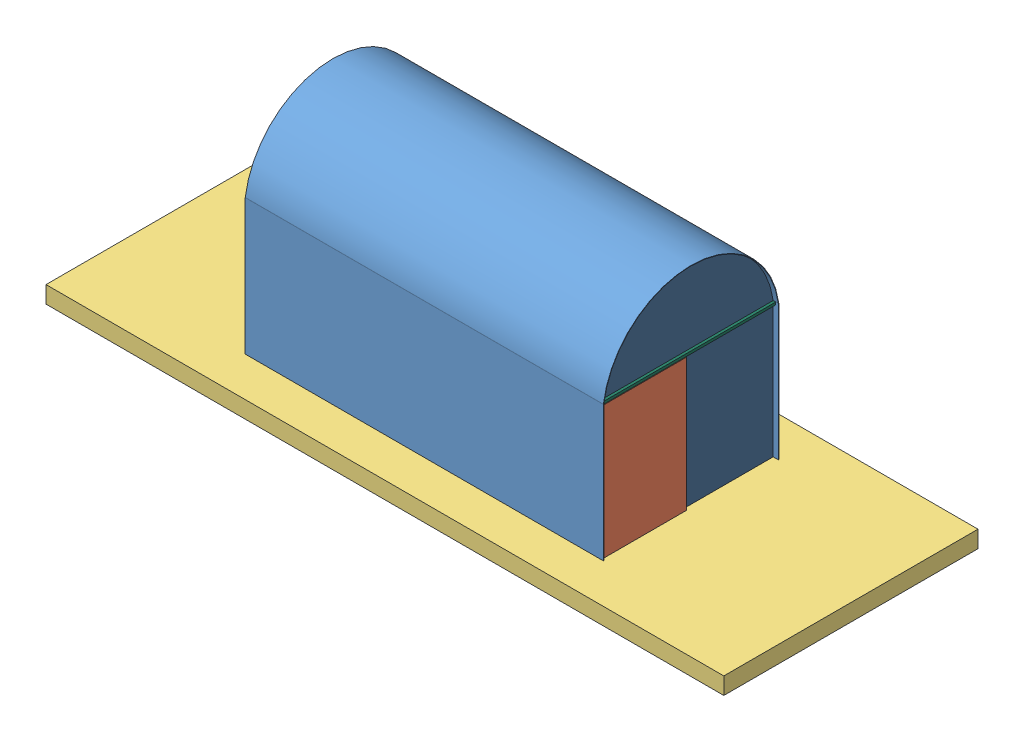
SolidWorks assembly SolarDryer, configuration Default. Lengths in mm.
Overall size (8000 2703.29 3000).
127 component instances, 22 part files, 14 mates.
Components (placement in the parent):
- Dome_-1: Dome_ [Default] x (-1 0 0) z (0 0 -1) size (4227 2503.29 2069.91)
- SolarDryer_Frame-1: SolarDryer_Frame [Default] at (-4192.3996 -838.53 0) x (0 0 1) z (-1 0 0) size (2062 2546.04 4095)
  - Vertical joint-1: Vertical joint [Default] at (-1015 770.5 -2160.8996) size (32 80 32)
  - VerticalBar-1: VerticalBar [Default] at (-425 0 -2160.8996) x (-1 0 0) z (0 0 1) size (30 1615 30)
  - Wrapper-1: Wrapper [Default] at (-425 780.5 -2160.8996) x (0 0 -1) z (0 1 0) size (22 32 30)
  - Arc_Bar-1: Arc_Bar [Default] at (0 838.5301 -2160.8996) x (0 0 -1) z (1 0 0) size (30.03 960.01 2060)
  - LateralBar-1: LateralBar [Default] at (0 826.5 -2160.8996) x (0 0 -1) z (1 0 0) size (30 30 1992)
  - Back_Wall-1: Back_Wall [Default] at (0 800 -2178.3996) size (2060 2500 5) (hidden)
  - Wrapper-4: Wrapper [Default] at (-1027 826.5 -2160.8996) x (0 1 0) z (1 0 0) size (22 32 30)
  - Wrapper-5: Wrapper [Default] at (-969 826.5 -2160.8996) x (0 0 1) z (-1 0 0) size (22 32 30)
  - VerticalBar_Corners-1: VerticalBar_Corners [Default] at (-1015 -14.4849 -2160.8996) size (30 1586.03 30)
  - Wrapper-8: Wrapper [Default] at (-425 838.5 -2160.8996) x (1 0 0) z (0 -1 0) size (22 32 30)
  - VerticalBar-2: VerticalBar [Default] at (425 0 -2160.8996) x (1 0 0) z (0 0 -1) size (30 1615 30)
  - Wrapper-9: Wrapper [Default] at (425 838.5 -2160.8996) x (1 0 0) z (0 -1 0) size (22 32 30)
  - Wrapper-10: Wrapper [Default] at (425 780.5 -2160.8996) x (0 0 1) z (0 1 0) size (22 32 30)
  - VerticalBar_Corners-2: VerticalBar_Corners [Default] at (1015 -14.4849 -2160.8996) x (-1 0 0) z (0 0 -1) size (30 1586.03 30)
  - Vertical joint-2: Vertical joint [Default] at (1015 770.5 -2160.8996) x (-1 0 0) z (0 0 -1) size (32 80 32)
  - Wrapper-11: Wrapper [Default] at (1027 826.5 -2160.8996) x (0 -1 0) z (-1 0 0) size (22 32 30)
  - Wrapper-12: Wrapper [Default] at (969 826.5 -2160.8996) x (0 0 -1) z (1 0 0) size (22 32 30)
  - VerticalBar_Corners-7: VerticalBar_Corners [Default] at (-1015 -14.4849 -4192.3996) size (30 1586.03 30)
  - VerticalBar_Corners-8: VerticalBar_Corners [Default] at (-1015 -14.4849 -6223.8996) size (30 1586.03 30)
  - Vertical joint-7: Vertical joint [Default] at (-1015 770.5 -4192.3996) size (32 80 32)
  - Vertical joint-8: Vertical joint [Default] at (-1015 770.5 -6223.8996) size (32 80 32)
  - VerticalBar_Corners-9: VerticalBar_Corners [Default] at (1015 -14.4849 -4192.3996) x (-1 0 0) z (0 0 -1) size (30 1586.03 30)
  - VerticalBar_Corners-10: VerticalBar_Corners [Default] at (1015 -14.4849 -6223.8996) x (-1 0 0) z (0 0 -1) size (30 1586.03 30)
  - Vertical joint-9: Vertical joint [Default] at (1015 770.5 -4192.3996) x (-1 0 0) z (0 0 -1) size (32 80 32)
  - Vertical joint-10: Vertical joint [Default] at (1015 770.5 -6223.8996) x (-1 0 0) z (0 0 -1) size (32 80 32)
  - Arc_Bar-4: Arc_Bar [Default] at (0 838.5301 -4192.3996) x (0 0 -1) z (1 0 0) size (30.03 960.01 2060)
  - Arc_Bar-5: Arc_Bar [Default] at (0 838.5301 -6223.8996) x (0 0 -1) z (1 0 0) size (30.03 960.01 2060)
  - Wrapper-13: Wrapper [Default] at (1015 719.5 -2148.8996) x (0 1 0) z (0 0 -1) size (22 32 30)
  - Wrapper-15: Wrapper [Default] at (1015 717.5 -2206.8996) size (22 32 30)
  - Wrapper-16: Wrapper [Default] at (1015 719.5 -4204.3996) x (0 -1 0) z (0 0 1) size (22 32 30)
  - Wrapper-17: Wrapper [Default] at (1015 717.5 -4146.3996) x (-1 0 0) z (0 0 -1) size (22 32 30)
  - HorizontalBarSides-1: HorizontalBarSides [Default] at (1015 717.5 -4174.3996) size (30 30 1995.5)
  - Wrapper-22: Wrapper [Default] at (1015 697.5 -4180.3996) x (0 1 0) z (0 0 -1) size (22 32 30)
  - Wrapper-23: Wrapper [Default] at (1015 695.5 -4238.3996) size (22 32 30)
  - HorizontalBarSides-3: HorizontalBarSides [Default] at (1015 695.5 -6205.8996) size (30 30 1995.5)
  - Wrapper-24: Wrapper [Default] at (1015 697.5 -6235.8996) x (0 -1 0) z (0 0 1) size (22 32 30)
  - Wrapper-25: Wrapper [Default] at (1015 695.5 -6177.8996) x (-1 0 0) z (0 0 -1) size (22 32 30)
  - Wrapper-26: Wrapper [Default] at (1015 147.5 -6235.8996) x (0 -1 0) z (0 0 1) size (22 32 30)
  - Wrapper-27: Wrapper [Default] at (1015 -402.5 -6235.8996) x (0 -1 0) z (0 0 1) size (22 32 30)
  - Wrapper-28: Wrapper [Default] at (1015 145.5 -6177.8996) x (-1 0 0) z (0 0 -1) size (22 32 30)
  - Wrapper-29: Wrapper [Default] at (1015 -404.5 -6177.8996) x (-1 0 0) z (0 0 -1) size (22 32 30)
  - HorizontalBarSides-4: HorizontalBarSides [Default] at (1015 145.5 -6205.8996) size (30 30 1995.5)
  - HorizontalBarSides-5: HorizontalBarSides [Default] at (1015 -404.5 -6205.8996) size (30 30 1995.5)
  - Wrapper-30: Wrapper [Default] at (1015 145.5 -4238.3996) size (22 32 30)
  - Wrapper-31: Wrapper [Default] at (1015 -404.5 -4238.3996) size (22 32 30)
  - Wrapper-32: Wrapper [Default] at (1015 147.5 -4180.3996) x (0 1 0) z (0 0 -1) size (22 32 30)
  - Wrapper-33: Wrapper [Default] at (1015 -402.5 -4180.3996) x (0 1 0) z (0 0 -1) size (22 32 30)
  - Wrapper-34: Wrapper [Default] at (1015 169.5 -4204.3996) x (0 -1 0) z (0 0 1) size (22 32 30)
  - Wrapper-35: Wrapper [Default] at (1015 -380.5 -4204.3996) x (0 -1 0) z (0 0 1) size (22 32 30)
  - Wrapper-36: Wrapper [Default] at (1015 167.5 -4146.3996) x (-1 0 0) z (0 0 -1) size (22 32 30)
  - Wrapper-37: Wrapper [Default] at (1015 -382.5 -4146.3996) x (-1 0 0) z (0 0 -1) size (22 32 30)
  - HorizontalBarSides-6: HorizontalBarSides [Default] at (1015 167.5 -4174.3996) size (30 30 1995.5)
  - HorizontalBarSides-7: HorizontalBarSides [Default] at (1015 -382.5 -4174.3996) size (30 30 1995.5)
  - Wrapper-38: Wrapper [Default] at (1015 169.5 -2148.8996) x (0 1 0) z (0 0 -1) size (22 32 30)
  - Wrapper-39: Wrapper [Default] at (1015 -380.5 -2148.8996) x (0 1 0) z (0 0 -1) size (22 32 30)
  - Wrapper-40: Wrapper [Default] at (1015 167.5 -2206.8996) size (22 32 30)
  - Wrapper-41: Wrapper [Default] at (1015 -382.5 -2206.8996) size (22 32 30)
  - Wrapper-42: Wrapper [Default] at (-1015 697.5 -6235.8996) x (0 1 0) z (0 0 1) size (22 32 30)
  - Wrapper-43: Wrapper [Default] at (-1015 695.5 -6177.8996) x (-1 0 0) z (0 0 -1) size (22 32 30)
  - HorizontalBarSides-8: HorizontalBarSides [Default] at (-1015 695.5 -4210.3996) x (-1 0 0) z (0 0 -1) size (30 30 1995.5)
  - Wrapper-44: Wrapper [Default] at (-1015 695.5 -4238.3996) size (22 32 30)
  - Wrapper-45: Wrapper [Default] at (-1015 697.5 -4180.3996) x (0 -1 0) z (0 0 -1) size (22 32 30)
  - Wrapper-46: Wrapper [Default] at (-1015 719.5 -4204.3996) x (0 1 0) z (0 0 1) size (22 32 30)
  - Wrapper-47: Wrapper [Default] at (-1015 717.5 -4146.3996) x (-1 0 0) z (0 0 -1) size (22 32 30)
  - HorizontalBarSides-9: HorizontalBarSides [Default] at (-1015 717.5 -2178.8996) x (-1 0 0) z (0 0 -1) size (30 30 1995.5)
  - Wrapper-48: Wrapper [Default] at (-1015 719.5 -2148.8996) x (0 -1 0) z (0 0 -1) size (22 32 30)
  - Wrapper-49: Wrapper [Default] at (-1015 717.5 -2206.8996) size (22 32 30)
  - Wrapper-50: Wrapper [Default] at (-1015 147.5 -6235.8996) x (0 1 0) z (0 0 1) size (22 32 30)
  - Wrapper-51: Wrapper [Default] at (-1015 -402.5 -6235.8996) x (0 1 0) z (0 0 1) size (22 32 30)
  - Wrapper-52: Wrapper [Default] at (-1015 145.5 -6177.8996) x (-1 0 0) z (0 0 -1) size (22 32 30)
  - Wrapper-53: Wrapper [Default] at (-1015 -404.5 -6177.8996) x (-1 0 0) z (0 0 -1) size (22 32 30)
  - HorizontalBarSides-10: HorizontalBarSides [Default] at (-1015 145.5 -4210.3996) x (-1 0 0) z (0 0 -1) size (30 30 1995.5)
  - HorizontalBarSides-11: HorizontalBarSides [Default] at (-1015 -404.5 -4210.3996) x (-1 0 0) z (0 0 -1) size (30 30 1995.5)
  - Wrapper-54: Wrapper [Default] at (-1015 145.5 -4238.3996) size (22 32 30)
  - Wrapper-55: Wrapper [Default] at (-1015 -404.5 -4238.3996) size (22 32 30)
  - Wrapper-56: Wrapper [Default] at (-1015 147.5 -4180.3996) x (0 -1 0) z (0 0 -1) size (22 32 30)
  - Wrapper-57: Wrapper [Default] at (-1015 -402.5 -4180.3996) x (0 -1 0) z (0 0 -1) size (22 32 30)
  - Wrapper-58: Wrapper [Default] at (-1015 169.5 -4204.3996) x (0 1 0) z (0 0 1) size (22 32 30)
  - Wrapper-59: Wrapper [Default] at (-1015 -380.5 -4204.3996) x (0 1 0) z (0 0 1) size (22 32 30)
  - Wrapper-60: Wrapper [Default] at (-1015 167.5 -4146.3996) x (-1 0 0) z (0 0 -1) size (22 32 30)
  - Wrapper-61: Wrapper [Default] at (-1015 -382.5 -4146.3996) x (-1 0 0) z (0 0 -1) size (22 32 30)
  - HorizontalBarSides-12: HorizontalBarSides [Default] at (-1015 167.5 -2178.8996) x (-1 0 0) z (0 0 -1) size (30 30 1995.5)
  - HorizontalBarSides-13: HorizontalBarSides [Default] at (-1015 -382.5 -2178.8996) x (-1 0 0) z (0 0 -1) size (30 30 1995.5)
  - Wrapper-62: Wrapper [Default] at (-1015 169.5 -2148.8996) x (0 -1 0) z (0 0 -1) size (22 32 30)
  - Wrapper-63: Wrapper [Default] at (-1015 -380.5 -2148.8996) x (0 -1 0) z (0 0 -1) size (22 32 30)
  - Wrapper-64: Wrapper [Default] at (-1015 167.5 -2206.8996) size (22 32 30)
  - Wrapper-65: Wrapper [Default] at (-1015 -382.5 -2206.8996) size (22 32 30)
- Back_SolarDryer-1: Back_SolarDryer [Default] at (-2050 -800.159 0) x (0 0 -1) z (1 0 0) size (2060 2500 5)
- FullFront-1: FullFront [Default] at (2050 -800.1591 0) x (0 0 -1) z (1 0 0) size (2060 2500 40)
  - Front_SolarDryer-1: Front_SolarDryer [Default] at origin size (2060 2500 5)
  - FullDoorWithBar-1: FullDoorWithBar [Default] at (0 785 17.5) x (0 0 1) z (-1 0 0) size (30 1600 2060)
    - FullCar-1: FullCar [Default] at (0 -6.25 870) size (25 18.99 35)
      - Carriage-1: Carriage [Default] at origin size (24.16 8.5 35)
      - LockWheels-1: LockWheels [Default] at (12.5 0 7.5) x (0 0.86398 0.503526) z (0 -0.503526 0.86398) size (3.5 7.63 3.5)
      - LockWheels-2: LockWheels [Default] at (12.5 0 -7.5) x (0 -0.86398 0.503526) z (0 -0.503526 -0.86398) size (3.5 7.63 3.5)
      - LockWheels-3: LockWheels [Default] at (-12.5 0 7.5) x (0 -0.86398 -0.503526) z (0 -0.503526 0.86398) size (3.5 7.63 3.5)
      - LockWheels-4: LockWheels [Default] at (-12.5 0 -7.5) x (0 0.86398 -0.503526) z (0 -0.503526 -0.86398) size (3.5 7.63 3.5)
      - WheelCarriage-1: WheelCarriage [Default] at (9.25 0 7.5) x (0 -0.862763 -0.505608) z (1 0 0) size (13.5 13.5 3.5)
      - WheelCarriage-2: WheelCarriage [Default] at (9.25 0 -7.5) x (0 -0.862763 0.505608) z (-1 0 0) size (13.5 13.5 3.5)
      - WheelCarriage-3: WheelCarriage [Default] at (-9.25 0 7.5) x (0 -0.862763 -0.505608) z (1 0 0) size (13.5 13.5 3.5)
      - WheelCarriage-4: WheelCarriage [Default] at (-9.25 0 -7.5) x (0 -0.862763 0.505608) z (-1 0 0) size (13.5 13.5 3.5)
      - Support-1: Support [Default] at (0 -7.5 0) x (0 0 1) z (-1 0 0) size (13 7.5 7)
    - FrontHorizontalBar-1: FrontHorizontalBar [Default] at origin size (30 30 2060)
    - Door-1: Door [Default] at (0 -801.125 530) x (0 0 1) z (-1 0 0) size (1000 1572.75 30)
    - Lid_Locker-1: Lid_Locker [Default] at (-3.725 -13.75 870) x (0 0 1) z (-1 0 0) size (13.9 5.5 1.7)
    - FullCar-4: FullCar [Default] at (0 -6.25 190) size (25 18.99 35)
      - Carriage-1: Carriage [Default] at origin size (24.16 8.5 35)
      - LockWheels-1: LockWheels [Default] at (12.5 0 7.5) x (0 0.86398 0.503526) z (0 -0.503526 0.86398) size (3.5 7.63 3.5)
      - LockWheels-2: LockWheels [Default] at (12.5 0 -7.5) x (0 -0.86398 0.503526) z (0 -0.503526 -0.86398) size (3.5 7.63 3.5)
      - LockWheels-3: LockWheels [Default] at (-12.5 0 7.5) x (0 -0.86398 -0.503526) z (0 -0.503526 0.86398) size (3.5 7.63 3.5)
      - LockWheels-4: LockWheels [Default] at (-12.5 0 -7.5) x (0 0.86398 -0.503526) z (0 -0.503526 -0.86398) size (3.5 7.63 3.5)
      - WheelCarriage-1: WheelCarriage [Default] at (9.25 0 7.5) x (0 -0.862763 -0.505608) z (1 0 0) size (13.5 13.5 3.5)
      - WheelCarriage-2: WheelCarriage [Default] at (9.25 0 -7.5) x (0 -0.862763 0.505608) z (-1 0 0) size (13.5 13.5 3.5)
      - WheelCarriage-3: WheelCarriage [Default] at (-9.25 0 7.5) x (0 -0.862763 -0.505608) z (1 0 0) size (13.5 13.5 3.5)
      - WheelCarriage-4: WheelCarriage [Default] at (-9.25 0 -7.5) x (0 -0.862763 0.505608) z (-1 0 0) size (13.5 13.5 3.5)
      - Support-1: Support [Default] at (0 -7.5 0) x (0 0 1) z (-1 0 0) size (13 7.5 7)
    - Lid_Locker-2: Lid_Locker [Default] at (-3.725 -13.75 190) x (0 0 1) z (-1 0 0) size (13.9 5.5 1.7)
    - Full_Restrictor-1: Full_Restrictor [Default] at (0 -12.75 897.6) x (-1 0 0) z (0 0 -1) size (25 10.16 20.1)
      - Lid_Restrictor-1: Lid_Restrictor [Default] at (0 8.5 10.1) x (1 0 0) z (0 0 -1) size (2.81 2.81 3)
      - Restrictor-1: Restrictor [Default] at origin size (25 9.5 19.9)
    - Full_Restrictor-2: Full_Restrictor [Default] at (0 -12.75 -897.6) size (25 10.16 20.1)
      - Lid_Restrictor-1: Lid_Restrictor [Default] at (0 8.5 10.1) x (1 0 0) z (0 0 -1) size (2.81 2.81 3)
      - Restrictor-1: Restrictor [Default] at origin size (25 9.5 19.9)
  - DoorCover-1: DoorCover [Default] at (-530 -16.125 35) size (1000 1567.75 5)
- Floor-1: Floor [Default] at (0 -1698.2927 0) x (-1 0 0) z (0 0 1) size (8000 200 3000)
Mates (geometry in assembly coordinates):
- Coincident6: coincident anti-aligned: plane of Dome_-1; plane of SolarDryer_Frame-1 through (-4192.3996 -838.53 0) normal (0 0 1)
- Coincident7: coincident anti-aligned: plane of Dome_-1 through (0 0 0) normal (-1 0 0)
- Coincident8: coincident anti-aligned: unknown of Dome_-1
- Coincident9: coincident aligned: plane of Dome_-1 through (0 0 0) normal (0 1 0)
- Coincident10: coincident anti-aligned: plane of Dome_-1 through (0 0 0) normal (-1 0 0)
- Tangent1: tangent aligned: cylinder of Dome_-1 through (-2113.5 -139.548 0) axis (1 0 0) radius 1039.548; face of SolarDryer_Frame-1/Arc_Bar-1
- Coincident13: coincident anti-aligned: plane of SolarDryer_Frame-1/Wrapper-9 through (-2047.5 -27.03 414) normal (-1 0 0); plane of Back_SolarDryer-1 through (-2047.5 -139.5479 0) normal (1 0 0)
- Concentric1: concentric aligned: circle of SolarDryer_Frame-1/Arc_Bar-1; circle of Back_SolarDryer-1
- Coincident14: coincident anti-aligned: plane of SolarDryer_Frame-1/Vertical joint-10 through (2047.5 -28.03 999) normal (1 0 0); plane of FullFront-1/Front_SolarDryer-1 through (2047.5 -139.548 0) normal (-1 0 0)
- Concentric3: concentric aligned: circle of Dome_-1; circle of FullFront-1/Front_SolarDryer-1
- Coincident15: coincident anti-aligned: plane of Dome_-1; plane of Floor-1 through (0 -1698.2927 0) normal (0 0 1)
- Coincident16: coincident aligned: plane of Dome_-1 through (0 0 0) normal (-1 0 0); plane of Floor-1 through (0 -1698.2927 0) normal (-1 0 0)
- Coincident17: coincident anti-aligned: plane of Dome_-1 through (-2113.5 -1598.2927 1034.9534) normal (0 -1 0); plane of Floor-1 through (0 -1598.2927 0) normal (0 1 0)
- Parallel1: parallel anti-aligned: plane of FullFront-1/FullDoorWithBar-1/Door-1 through (2052.5 -1600.1591 30) normal (0 -1 0); plane of Floor-1 through (0 -1598.2927 0) normal (0 1 0)
